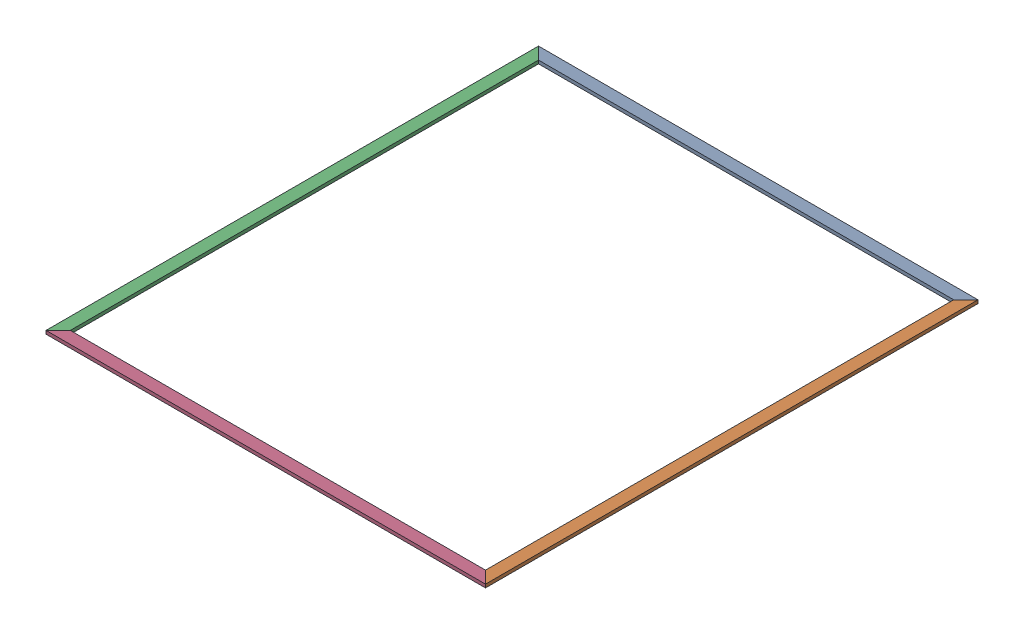
SolidWorks assembly crown, configuration Default. Lengths in mm.
Overall size (5054.6 38.1 5664.2).
4 component instances, 2 part files, 24 mates.
Components (placement in the parent):
- 2x6x199-Chamfered-1: 2x6x199-Chamfered [Default] at (-2527.3 0 -2762.25) x (0 0 -1) z (0 -1 0) size (139.7 5054.6 38.1)
- 2x6x223-Chamfered-1: 2x6x223-Chamfered [Default] at (2457.45 0 2832.1) x (1 0 0) z (0 1 0) size (139.7 5664.2 38.1)
- 2x6x223-Chamfered-2: 2x6x223-Chamfered [Default] at (-2457.45 0 2832.1) x (-1 0 0) z (0 -1 0) size (139.7 5664.2 38.1)
- 2x6x199-Chamfered-3: 2x6x199-Chamfered [Default] at (-2527.3 0 2762.25) x (0 0 1) z (0 1 0) size (139.7 5054.6 38.1)
Mates (geometry in assembly coordinates):
- Coincident2: coordinate: point of 2x6x196-1
- Coincident7: coincident: unknown of 2x6x196-2
- Parallel1: parallel anti-aligned: plane of 2x6x196-2 through (4978.4 -69.85 -19.05) normal (0 -1 0)
- Parallel2: parallel: line of 2x6x196-2 through (4978.4 69.85 19.05) axis (-1 0 0)
- Symmetric1: symmetric aligned: plane of plastic sheeting 216x192-1 through (4927.6 -69.85 4248.15) normal (0 0 1); plane of plastic sheeting 216x192-1 through (4927.6 -69.85 -1238.25) normal (0 0 -1)
- Symmetric2: symmetric aligned: plane of plastic sheeting 216x192-1 through (4927.6 -69.85 4248.15) normal (1 0 0); plane of plastic sheeting 216x192-1 through (50.8 -69.85 4248.15) normal (-1 0 0)
- Coincident44: coincident anti-aligned: plane of 2x6x196-2 through (4978.4 -69.85 -19.05) normal (0 -1 0); plane of plastic sheeting 216x192-1 through (2489.2 -69.85 1504.95) normal (0 1 0)
- Coincident79: coincident anti-aligned: line of 2x6x199-Chamfered-1 through (5016.5 -107.95 -1327.15) axis (0 1 0); line of 2x6x199-Chamfered-2 through (4651.4718 6844.1044 4973.8507) axis (0 0 1)
- Coincident80: coincident anti-aligned: plane of 2x6x199-Chamfered-1 through (5016.5 -107.95 -1327.15) normal (0.707107 0 0.707107); plane of 2x6x199-Chamfered-2 through (4651.4718 6844.1044 4973.8507) normal (0.707107 -0.707107 0)
- Coincident81: coincident aligned: plane of 2x6x199-Chamfered-1 through (5016.5 -69.85 -1187.45) normal (0 1 0); plane of 2x6x199-Chamfered-2 through (4651.4718 6704.4044 4973.8507) normal (0 0 -1)
- Coincident82: coincident aligned: plane of 2x6x199-Chamfered-1 through (4734.436 310.2798 -1285.454) normal (0 1 0); plane of 2x6x223-Chamfered-2 through (-180.464 310.2798 -1425.154) normal (0 1 0)
- Coincident83: coincident aligned: line of 2x6x199-Chamfered-1 through (-320.164 272.1798 -1425.154) axis (0 1 0); line of 2x6x223-Chamfered-2 through (-320.164 272.1798 -1425.154) axis (0 1 0)
- Coincident84: coincident anti-aligned: plane of 2x6x199-Chamfered-1 through (-320.164 272.1798 -1425.154) normal (-0.707107 0 0.707107); plane of 2x6x223-Chamfered-2 through (-320.164 310.2798 -1425.154) normal (0.707107 0 -0.707107)
- Coincident85: coincident anti-aligned: line of 2x6x223-Chamfered-1 through (4876.8 -107.95 -1187.45) axis (0 1 0); line of 2x6x199-Chamfered-2 through (-263.4282 6704.4044 4973.8507) axis (0 0 1)
- Coincident86: coincident: point of 2x6x223-Chamfered-1; point of 2x6x199-Chamfered-2
- Coincident87: coincident anti-aligned: line of 2x6x199-Chamfered-1 through (4734.436 272.1798 -1425.154) axis (0 1 0); line of 2x6x223-Chamfered-1 through (4734.436 310.2798 -1425.154) axis (0 -1 0)
- Coincident88: coincident: point of 2x6x199-Chamfered-1; point of 2x6x223-Chamfered-1
- Coincident89: coincident aligned: line of 2x6x223-Chamfered-1 through (4734.436 310.2798 4239.046) axis (0 -1 0); line of 2x6x199-Chamfered-3 through (4734.436 310.2798 4239.046) axis (0 -1 0)
- Coincident90: coincident: point of 2x6x223-Chamfered-1; point of 2x6x199-Chamfered-3
- Coincident91: coincident anti-aligned: plane of 2x6x196-14 through (4978.4 -69.85 4210.05) normal (0 -1 0); plane of 2x6x223-Chamfered-1 through (4876.8 -69.85 -1327.15) normal (0 1 0)
- Coincident93: coincident anti-aligned: plane of 2x6x199-Chamfered-1 through (5016.5 -107.95 -1187.45) normal (0 -1 0); plane of plastic sheeting 216x192-2 through (2489.2 -107.95 1504.95) normal (0 1 0)
- Symmetric3: symmetric aligned: plane of 2x6x199-Chamfered-1 through (2527.3 -19.05 -2692.4) normal (0 0 1); plane of 2x6x199-Chamfered-3 through (2527.3 19.05 2692.4) normal (0 0 -1)
- Symmetric4: symmetric aligned: plane of 2x6x223-Chamfered-1 through (2387.6 19.05 -2832.1) normal (-1 0 0); plane of 2x6x223-Chamfered-2 through (-2387.6 -19.05 -2832.1) normal (1 0 0)
- Symmetric5: symmetric aligned: plane of 2x6x223-Chamfered-1 through (2387.6 19.05 -2832.1) normal (0 1 0); plane of 2x6x223-Chamfered-1 through (2387.6 -19.05 -2832.1) normal (0 -1 0)
